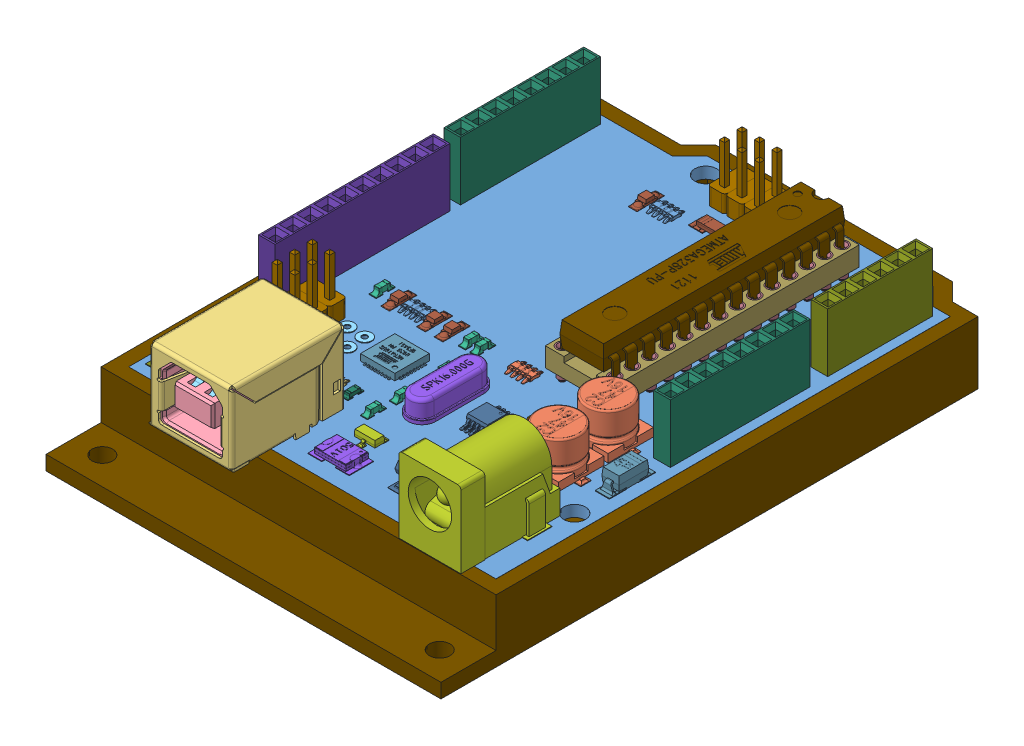
SolidWorks assembly holderAssem, configuration Default. Lengths in mm.
Overall size (57.36 20.15 80.54).
89 component instances, 36 part files, 3 mates.
Components (placement in the parent):
- arduino uno-1: arduino uno [Default] at (33.3982 23.6972 65.1649) size (53.34 15.25 74.97)
  - unoboard blue-1: unoboard blue [Default] at origin size (53.34 1.65 68.58)
  - 47uf CAP Dcase-1: 47uf CAP Dcase [Default] at (-9.4141 0 -18.4991) x (0 0 -1) z (1 0 0) size (6.6 5.81 8)
  - USB type b-1: USB type b [Default] at (-38.02 0.43 6.35) size (14.34 15.2 16.54)
    - USB SHELL-1: USB SHELL [Default] at origin size (14.34 15.2 16.54)
    - USB core-1: USB core [Default] at origin size (11.3 10.68 15.75)
    - usb top contact-1: usb top contact [Default] at (1.25 6.09 -0.38) size (1 9.67 13.76)
    - usb btm contact-1: usb btm contact [Default] at (1.25 4.41 -0.38) size (1 6.84 11.76)
    - usb btm contact-2: usb btm contact [Default] at (-1.25 4.41 -0.38) size (1 6.84 11.76)
    - usb top contact-2: usb top contact [Default] at (-1.25 6.09 -0.38) size (1 9.67 13.76)
  - power jack-1: power jack [Default] at (-7.675 0 1.905) size (11.2 15.2 15.9)
  - 47uf CAP Dcase-2: 47uf CAP Dcase [Default] at (-9.4141 0 -25.7132) x (0 0 -1) z (1 0 0) size (6.6 5.81 8)
  - crystal-1: crystal [Default] at (-26.162 0 -18.923) x (1 0 0) z (0 0 -1) size (4 5 11)
  - 2pin_header__02-1: 2pin_header__02 [Default] at (-46.23 0 -15.75) size (5 11.75 2.54)
  - nano - reg-1: nano - reg [Default] at (-17.399 0 -7.747) size (6.5 1.69 8.3)
  - led-1: led [Default] at (-34.29 0 -27.94) x (0 0 1) z (-1 0 0) size (4 0.86 1.35)
  - 2pin_header__02-2: 2pin_header__02 [Default] at (-30.43 0 -64.91) x (0 0 1) z (-1 0 0) size (5 11.75 2.54)
  - dip28-1: dip28 [Default] at (-16.383 1.5 -46.355) x (0 0 -1) z (1 0 0) size (35.48 7.37 10.1)
    - dip28-1: dip28 [Default] at origin size (35.48 2.8 10.1)
    - dip socket pin-1: dip socket pin [Default] at (16.51 2.8 -3.81) size (1.7 7.37 1.7)
    - dip socket pin-2: dip socket pin [Default] at (16.51 2.8 3.81) size (1.7 7.37 1.7)
    - dip socket pin-3: dip socket pin [Default] at (13.97 2.8 -3.81) size (1.7 7.37 1.7)
    - dip socket pin-4: dip socket pin [Default] at (13.97 2.8 3.81) size (1.7 7.37 1.7)
    - dip socket pin-5: dip socket pin [Default] at (11.43 2.8 -3.81) size (1.7 7.37 1.7)
    - dip socket pin-6: dip socket pin [Default] at (11.43 2.8 3.81) size (1.7 7.37 1.7)
    - dip socket pin-7: dip socket pin [Default] at (8.89 2.8 -3.81) size (1.7 7.37 1.7)
    - dip socket pin-8: dip socket pin [Default] at (8.89 2.8 3.81) size (1.7 7.37 1.7)
    - dip socket pin-9: dip socket pin [Default] at (6.35 2.8 -3.81) size (1.7 7.37 1.7)
    - dip socket pin-10: dip socket pin [Default] at (6.35 2.8 3.81) size (1.7 7.37 1.7)
    - dip socket pin-11: dip socket pin [Default] at (3.81 2.8 -3.81) size (1.7 7.37 1.7)
    - dip socket pin-12: dip socket pin [Default] at (3.81 2.8 3.81) size (1.7 7.37 1.7)
    - dip socket pin-13: dip socket pin [Default] at (1.27 2.8 -3.81) size (1.7 7.37 1.7)
    - dip socket pin-14: dip socket pin [Default] at (1.27 2.8 3.81) size (1.7 7.37 1.7)
    - dip socket pin-15: dip socket pin [Default] at (-1.27 2.8 -3.81) size (1.7 7.37 1.7)
    - dip socket pin-16: dip socket pin [Default] at (-1.27 2.8 3.81) size (1.7 7.37 1.7)
    - dip socket pin-17: dip socket pin [Default] at (-3.81 2.8 -3.81) size (1.7 7.37 1.7)
    - dip socket pin-18: dip socket pin [Default] at (-3.81 2.8 3.81) size (1.7 7.37 1.7)
    - dip socket pin-19: dip socket pin [Default] at (-6.35 2.8 -3.81) size (1.7 7.37 1.7)
    - dip socket pin-20: dip socket pin [Default] at (-6.35 2.8 3.81) size (1.7 7.37 1.7)
    - dip socket pin-21: dip socket pin [Default] at (-8.89 2.8 -3.81) size (1.7 7.37 1.7)
    - dip socket pin-22: dip socket pin [Default] at (-8.89 2.8 3.81) size (1.7 7.37 1.7)
    - dip socket pin-23: dip socket pin [Default] at (-11.43 2.8 -3.81) size (1.7 7.37 1.7)
    - dip socket pin-24: dip socket pin [Default] at (-11.43 2.8 3.81) size (1.7 7.37 1.7)
    - dip socket pin-25: dip socket pin [Default] at (-13.97 2.8 -3.81) size (1.7 7.37 1.7)
    - dip socket pin-26: dip socket pin [Default] at (-13.97 2.8 3.81) size (1.7 7.37 1.7)
    - dip socket pin-27: dip socket pin [Default] at (-16.51 2.8 -3.81) size (1.7 7.37 1.7)
    - dip socket pin-28: dip socket pin [Default] at (-16.51 2.8 3.81) size (1.7 7.37 1.7)
  - 2pin_header__02-3: 2pin_header__02 [Default] at (-27.89 0 -64.91) x (0 0 1) z (-1 0 0) size (5 11.75 2.54)
  - 2pin_header__02-4: 2pin_header__02 [Default] at (-25.35 0 -64.91) x (0 0 1) z (-1 0 0) size (5 11.75 2.54)
  - 2pin_header__02-5: 2pin_header__02 [Default] at (-46.23 0 -18.29) size (5 11.75 2.54)
  - 2pin_header__02-6: 2pin_header__02 [Default] at (-46.23 0 -20.83) size (5 11.75 2.54)
  - atmega16u2-1: atmega16u2 [Default] at (-34.671 0.06 -20) x (1 0 0) z (0 0 -1) size (5.5 1.01 5.5)
  - led-2: led [Default] at (-36.83 0 -27.94) x (0 0 1) z (-1 0 0) size (4 0.86 1.35)
  - led-3: led [Default] at (-42.037 0 -27.94) x (0 0 1) z (-1 0 0) size (4 0.86 1.35)
  - led-4: led [Default] at (-36.576 0 -58.42) x (0 0 1) z (-1 0 0) size (4 0.86 1.35)
  - 8 PORT HEADER-3: 8 PORT HEADER [Default] at (-50.8 0 -45.72) x (0 0 -1) z (1 0 0) size (20.32 10.51 2.41)
  - 8 PORT HEADER-4: 8 PORT HEADER [Default] at (-2.54 0 -27.94) x (0 0 -1) z (1 0 0) size (20.32 10.51 2.41)
  - 6 PORT HEADER-3: 6 PORT HEADER [Default] at (-2.54 0 -50.8) x (0 0 -1) z (1 0 0) size (15.24 10.51 2.41)
  - 10 PORT HEADER-1: 10 PORT HEADER [Default] at (-50.8 0 -18.796) x (0 0 -1) z (1 0 0) size (25.4 10.51 2.41)
  - ATMEL328P-1: ATMEL328P [Default] at (-16.383 4.3 -46.355) x (0 0 -1) z (1 0 0) size (35 7.27 7.87)
  - 102 RESISTOR PACK-1: 102 RESISTOR PACK [Default] at (-33.782 0 -58.42) size (3.2 0.46 3)
  - 102 RESISTOR PACK-2: 102 RESISTOR PACK [Default] at (-39.37 0 -27.94) size (3.2 0.46 3)
  - 103 RESISTOR PACK-3: 103 RESISTOR PACK [Default] at (-23.876 0 -27.94) size (3.2 0.46 3)
  - 220 RESISTOR PACK-1: 220 RESISTOR PACK [Default] at (-36.83 0 -12.827) size (3.2 0.46 3)
  - 16mhz crystal - measured-1: 16mhz crystal - measured [Default] at (-24.892 0 -41.275) x (0 0 -1) z (1 0 0) size (3.4 0.8 2)
  - PADS001-1: PADS001 [Default] at (-39.878 0.1 -18.288) x (-1 0 0) z (0 0 1) size (4.54 0.1 4.54)
  - 603 cap on pad-1: 603 cap on pad [Default] at (-44.45 0 -27.94) x (0 0 -1) z (1 0 0) size (2.76 0.9 1.12)
  - ssot3-1: ssot3 [Default] at (-26.5 0 -8.128) x (-1 0 0) z (0 0 -1) size (3 1.13 3.09)
  - mf-msmf050-2-1: mf-msmf050-2 [Default] at (-26.5 0 -4.064) size (5.77 1.02 3.72)
  - 603 cap on pad-2: 603 cap on pad [Default] at (-29.845 0 -27.94) x (0 0 -1) z (1 0 0) size (2.76 0.9 1.12)
  - 603 cap on pad-3: 603 cap on pad [Default] at (-31.496 0 -27.94) x (0 0 -1) z (1 0 0) size (2.76 0.9 1.12)
  - lmv358-1: lmv358 [Default] at (-15.24 0 -21.971) x (0 0 -1) z (1 0 0) size (3.7 1.4 2.9)
  - 603 cap on pad-4: 603 cap on pad [Default] at (-15.24 0 -18.415) size (2.76 0.9 1.12)
  - 603 cap on pad-5: 603 cap on pad [Default] at (-29.845 0 -12.065) x (0 0 1) z (-1 0 0) size (2.76 0.9 1.12)
  - 603 cap on pad-6: 603 cap on pad [Default] at (-29.591 0 -22.352) x (0 0 1) z (-1 0 0) size (2.76 0.9 1.12)
  - 603 cap on pad-7: 603 cap on pad [Default] at (-29.591 0 -16.002) x (0 0 1) z (-1 0 0) size (2.76 0.9 1.12)
  - 603 cap on pad-8: 603 cap on pad [Default] at (-41.91 0 -12.7) x (0 0 1) z (-1 0 0) size (2.76 0.9 1.12)
  - lp2985dgkr-1: lp2985dgkr [Default] at (-20.32 0 -19.05) x (0 0 -1) z (1 0 0) size (5.85 1.1 3)
  - cd1206 diode-1: cd1206 diode [Default] at (-27.94 0 -59.436) x (0 0 -1) z (1 0 0) size (2.07 0.96 5)
  - cd1206 diode-2: cd1206 diode [Default] at (-46.228 0 -13.081) x (0 0 1) z (-1 0 0) size (2.07 0.96 5)
  - 603 resistor-1: 603 resistor [Default] at (-29.591 0 -19.05) x (0 0 1) z (-1 0 0) size (2.36 0.61 1.03)
  - blm21-1: blm21 [Default] at (-45.085 0 -7.62) x (0 0 -1) z (1 0 0) size (2.76 0.95 1.32)
  - m7 diode-1: m7 diode [Default] at (-2.794 0 -21.59) x (0 0 -1) z (1 0 0) size (6.66 2.35 2.5)
  - MLC0603-1: MLC0603 [Default] at (-33.655 0 -12.827) x (0 0 -1) z (1 0 0) size (2.36 0.6 1.03)
  - MLC0603-2: MLC0603 [Default] at (-39.37 0 -12.827) x (0 0 -1) z (1 0 0) size (2.36 0.6 1.03)
  - RESET BUTTON-1: RESET BUTTON [Default] at (-49.403 0 -6.35) size (6.2 3.1 9.6)
    - RESET CORE-1: RESET CORE [Default] at (0 0.1 0) x (-1 0 0) z (0 0 -1) size (6.2 3.1 9.6)
    - RESET-1: RESET [Default] at (0 0.1 0) x (0 0 1) z (-1 0 0) size (7.3 2 6.2)
- arduino holder-1: arduino holder [Default] at (6.7382 14.5972 75.1649) x (-1 0 0) z (0 0 -1) size (57.36 9.1 80.54)
Mates (geometry in assembly coordinates):
- Coincident1: coincident: plane of arduino uno-1/unoboard blue-1 through (33.3982 23.6972 65.1649) normal (0 1 0); plane of arduino holder-1 through (6.7382 23.6972 75.1649) normal (0 1 0)
- Coincident2: coincident: plane of arduino uno-1/unoboard blue-1 through (-19.9418 22.0472 65.1649) normal (-1 0 0); plane of arduino holder-1 through (-19.9418 16.6972 65.1649) normal (1 0 0)
- Coincident3: coincident: plane of arduino uno-1/unoboard blue-1 through (33.3982 22.0472 65.1649) normal (0 0 1); plane of arduino holder-1 through (33.4182 16.6972 65.1649) normal (0 0 -1)
